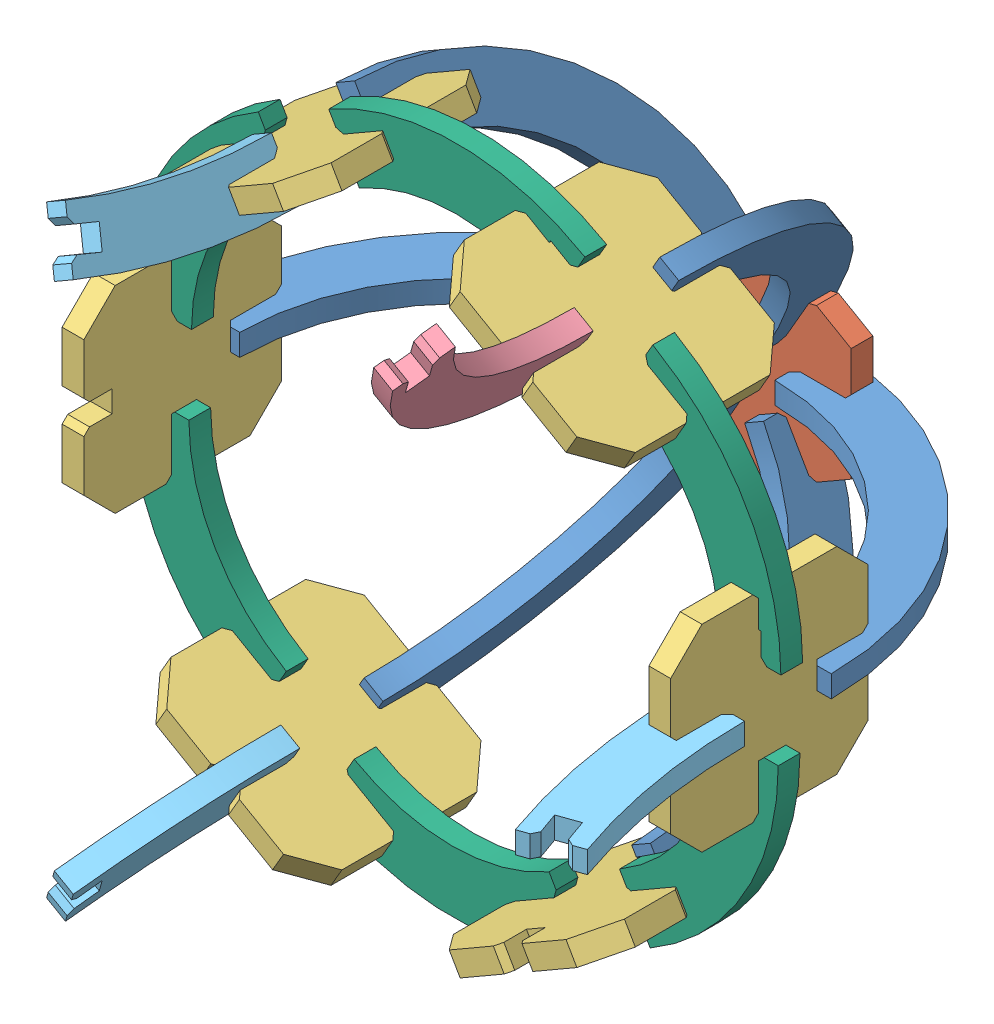
SolidWorks assembly Casquete1, configuration Default. Lengths in mm.
Overall size (138.23 154.01 159.67).
23 component instances, 6 part files, 22 mates.
Components (placement in the parent):
- Circle-1: Circle [Default] at (-65.1069 8.9145 39.0884) size (50 3.85 50)
- Hexagon-1: Hexagon [Default] at (-72.4274 10.8395 -4.4116) x (0.866025 0.5 0) z (-0.5 0.866025 0) size (40 54.12 34.64)
- Circle-2: Circle [Default] at (-70.4343 3.5373 39.0884) x (0.5 -0.866025 0) z (0 0 1) size (50 3.85 50)
- Circle-3: Circle [Default] at (-77.7548 5.4623 39.0884) x (-0.5 -0.866025 0) z (0 0 1) size (50 3.85 50)
- square-1: square [Default] at (-97.4127 54.1153 46.5492) x (0.866025 0.5 0) z (0 0 1) size (34.92 3.85 34.92)
- square-2: square [Default] at (-47.4422 54.1153 46.5492) x (0.866025 -0.5 0) z (0 0 1) size (34.92 3.85 34.92)
- square-3: square [Default] at (-22.4569 10.8395 46.5492) x (0 -1 0) z (0 0 1) size (34.92 3.85 34.92)
- Circle-8: Circle [Default] at (-79.7479 12.7645 39.0884) x (-1 0 0) z (0 0 1) size (50 3.85 50)
- Circle-9: Circle [Default] at (-74.4206 18.1418 39.0884) x (-0.5 0.866025 0) z (0 0 1) size (50 3.85 50)
- Circle-10: Circle [Default] at (-67.1001 16.2168 39.0884) x (0.5 0.866025 0) z (0 0 1) size (50 3.85 50)
- square-7: square [Default] at (-47.4422 -32.4362 46.5492) x (-0.866025 -0.5 0) z (0 0 1) size (34.92 3.85 34.92)
- square-8: square [Default] at (-97.4127 -32.4362 46.5492) x (-0.866025 0.5 0) z (0 0 1) size (34.92 3.85 34.92)
- square-9: square [Default] at (-122.3979 10.8395 46.5492) x (0 1 0) z (0 0 1) size (34.92 3.85 34.92)
- Circle120-1: Circle120 [Default] at (-34.3835 80.5835 102.8568) x (-0.166903 -0.289085 0.942641) z (0.471321 0.816351 0.333807) size (36.65 3.85 47.13)
- CircleConcavo-1: CircleConcavo [Default] at (-27.4089 8.9145 54.1757) x (-1 0 0) z (0 0 -1) size (15.77 3.85 36.9)
- CircleConcavo-2: CircleConcavo [Default] at (-96.6038 -27.1852 54.1757) x (0.5 0.866025 0) z (0 0 -1) size (15.77 3.85 36.9)
- CircleConcavo-3: CircleConcavo [Default] at (-93.2696 50.7892 54.1757) x (0.5 -0.866025 0) z (0 0 -1) size (15.77 3.85 36.9)
- Circle60-7: Circle60 [Default] at (-59.9685 17.4976 48.4742) x (0.5 0.866025 0) z (-0.866025 0.5 0) size (28.09 3.85 39.25)
- Circle60-8: Circle60 [Default] at (-60.4319 3.3788 48.4742) x (1 0 0) z (0 1 0) size (28.09 3.85 39.25)
- Circle60-9: Circle60 [Default] at (-72.8909 -3.2793 48.4742) x (0.5 -0.866025 0) z (0.866025 0.5 0) size (28.09 3.85 39.25)
- Circle60-10: Circle60 [Default] at (-84.8864 4.1815 48.4742) x (-0.5 -0.866025 0) z (0.866025 -0.5 0) size (28.09 3.85 39.25)
- Circle60-11: Circle60 [Default] at (-84.4229 18.3003 48.4742) x (-1 0 0) z (0 -1 0) size (28.09 3.85 39.25)
- Circle60-12: Circle60 [Default] at (-71.964 24.9583 48.4742) x (-0.5 0.866025 0) z (-0.866025 -0.5 0) size (28.09 3.85 39.25)
Mates (geometry in assembly coordinates):
- Parallel1: parallel anti-aligned: plane of Circle-1 through (-65.1069 12.7645 -8.2616) normal (0 0 1); plane of Hexagon-1 through (-72.4274 10.8395 -8.2616) normal (0 0 -1)
- Coincident1: coincident anti-aligned: plane of Circle-1 through (-60.1069 12.7645 -8.2616) normal (-1 0 0); plane of Hexagon-1 through (-60.1069 8.9145 -8.2616) normal (1 0 0)
- Coincident2: coincident anti-aligned: plane of Circle-1 through (-65.1069 8.9145 39.0884) normal (0 -1 0); plane of Hexagon-1 through (-55.1069 8.9145 -8.2616) normal (0 1 0)
- Coincident3: coincident anti-aligned: plane of Circle-1 through (-65.1069 12.7645 -4.4116) normal (0 0 -1); plane of Hexagon-1 through (-72.4274 10.8395 -4.4116) normal (0 0 1)
- Parallel2: parallel anti-aligned: plane of ? through (-100.6367 56.2745 39.0884) normal (0.5 -0.866025 0); plane of square-1 through (-99.3377 57.0245 46.4084) normal (-0.5 0.866025 0)
- Coincident9: coincident anti-aligned: plane of ? through (-74.7886 17.5043 39.0884) normal (0.866025 0.5 0); plane of square-1 through (-98.0386 57.7745 29.0884) normal (-0.866025 -0.5 0)
- Coincident10: coincident anti-aligned: plane of ? through (-99.1367 53.6764 34.0884) normal (0 0 1); plane of square-1 through (-100.6367 56.2745 34.0884) normal (0 0 -1)
- Coincident12: coincident anti-aligned: plane of ? through (-126.2479 8.9145 39.0884) normal (1 0 0); plane of ? through (-126.2479 10.4145 46.4084) normal (-1 0 0)
- Coincident15: coincident anti-aligned: plane of square-2 through (-45.5172 57.4495 46.5492) normal (0.5 0.866025 0); plane of Circle120-1 through (-43.8501 56.487 54.0099) normal (-0.5 -0.866025 0)
- Coincident16: coincident anti-aligned: plane of square-2 through (-47.1843 58.412 64.0099) normal (0.866025 -0.5 0); plane of Circle120-1 through (-25.6468 95.716 54.0099) normal (-0.866025 0.5 0)
- Coincident17: coincident anti-aligned: plane of square-2 through (-43.8501 56.487 59.0099) normal (0 0 1); plane of Circle120-1 through (-45.7751 53.1528 59.0099) normal (0 0 -1)
- Coincident23: coincident anti-aligned: plane of square-3 through (-18.6069 8.9145 59.0099) normal (0 0 1); plane of CircleConcavo-1 through (-22.4569 12.7645 59.0099) normal (0 0 -1)
- Coincident28: coincident anti-aligned: plane of Circle-2 through (-70.4343 3.5373 39.0884) normal (-0.866025 -0.5 0); plane of square-7 through (-47.1843 -36.7329 29.0884) normal (0.866025 0.5 0)
- Coincident29: coincident anti-aligned: plane of Circle-2 through (-45.7751 -31.4737 34.0884) normal (0 0 1); plane of square-7 through (-43.8501 -34.8079 34.0884) normal (0 0 -1)
- Coincident33: coincident anti-aligned: plane of Circle-1 through (-18.6069 12.7645 39.0884) normal (-1 0 0); plane of square-3 through (-18.6069 10.8395 46.5492) normal (1 0 0)
- Coincident34: coincident anti-aligned: plane of Hexagon-1 through (-80.2548 1.1322 -8.2616) normal (-0.5 -0.866025 0); plane of Circle-3 through (-76.9206 -0.7928 -8.2616) normal (0.5 0.866025 0)
- Coincident35: coincident anti-aligned: plane of square-1 through (-97.6706 58.412 29.0884) normal (-0.866025 -0.5 0); plane of Circle-9 through (-74.4206 18.1418 39.0884) normal (0.866025 0.5 0)
- Coincident36: coincident anti-aligned: plane of square-3 through (-18.6069 12.7645 64.0099) normal (0 -1 0); plane of CircleConcavo-1 through (85.0133 12.7645 54.0099) normal (0 1 0)
- Coincident37: coincident anti-aligned: plane of square-3 through (-22.4569 10.8395 46.5492) normal (-1 0 0); plane of CircleConcavo-1 through (-22.4569 12.7645 54.0099) normal (1 0 0)
- Coincident38: coincident anti-aligned: plane of square-2 through (-30.3957 48.7191 44.6242) normal (0 0 1); plane of Circle60-7 through (-59.9685 17.4976 44.6242) normal (0 0 -1)
- Coincident39: coincident anti-aligned: plane of square-2 through (-47.4422 54.1153 46.5492) normal (-0.5 -0.866025 0); plane of Circle60-7 through (-40.981 50.3849 44.6242) normal (0.5 0.866025 0)
- Coincident40: coincident anti-aligned: plane of square-2 through (-34.7258 51.2191 44.6242) normal (0.866025 -0.5 0); plane of Circle60-7 through (-36.6508 47.8849 44.6242) normal (-0.866025 0.5 0)
